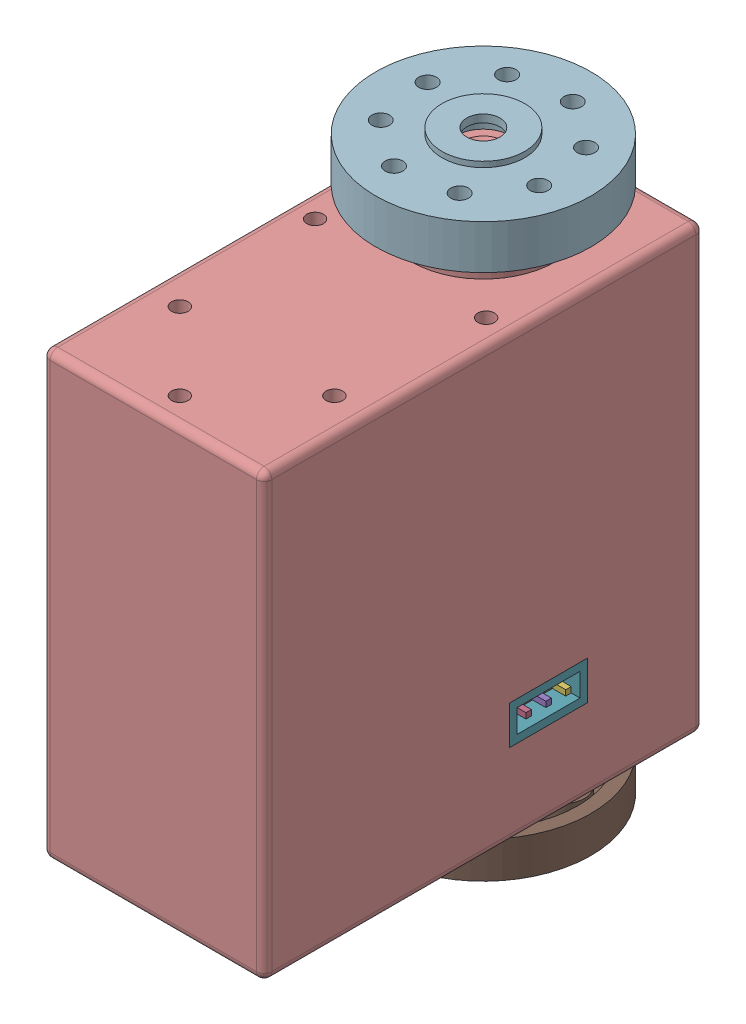
SolidWorks assembly LX-224 Asembled, configuration Predeterminado. Lengths in mm.
Overall size (26.99 53 43.41).
3 component instances, 3 part files, 4 mates.
Components (placement in the parent):
- LX-224 Servo-1: LX-224 Servo [Predeterminado] at origin size (20.09 51.1 39.82)
- BackHub-2: BackHub [Predeterminado] at (0 -43.3 0) x (-0.837169 0 -0.546944) z (-0.546944 0 0.837169) size (19.5 3.6 19.5)
- FrontHub-2: FrontHub [Predeterminado] at (0 4.8 0) x (0.97427 0 0.225385) z (-0.225385 0 0.97427) size (19.5 5 19.5)
Mates (geometry in assembly coordinates):
- Concéntrica5: concentric anti-aligned: cylinder of LX-224 Servo-1 through (0 1.4 0) axis (0 1 0) radius 1.25; cylinder of FrontHub-2 through (0 6.6 0) axis (0 -1 0) radius 2.5
- Distancia1: distance = 0.8 mm anti-aligned: plane of LX-224 Servo-1 through (0 1.5 0) normal (0 1 0); plane of FrontHub-2 through (0 2.3 0) normal (0 -1 0)
- Concéntrica6: concentric aligned: cylinder of LX-224 Servo-1 through (0 -45.7 0) axis (0 1 0) radius 3; cylinder of BackHub-2 through (0 -44.95 0) axis (0 1 0) radius 3
- Coincidente7: coincident anti-aligned: plane of LX-224 Servo-1 through (0 -41.5 0) normal (0 -1 0); plane of BackHub-2 through (0 -41.5 0) normal (0 1 0)
